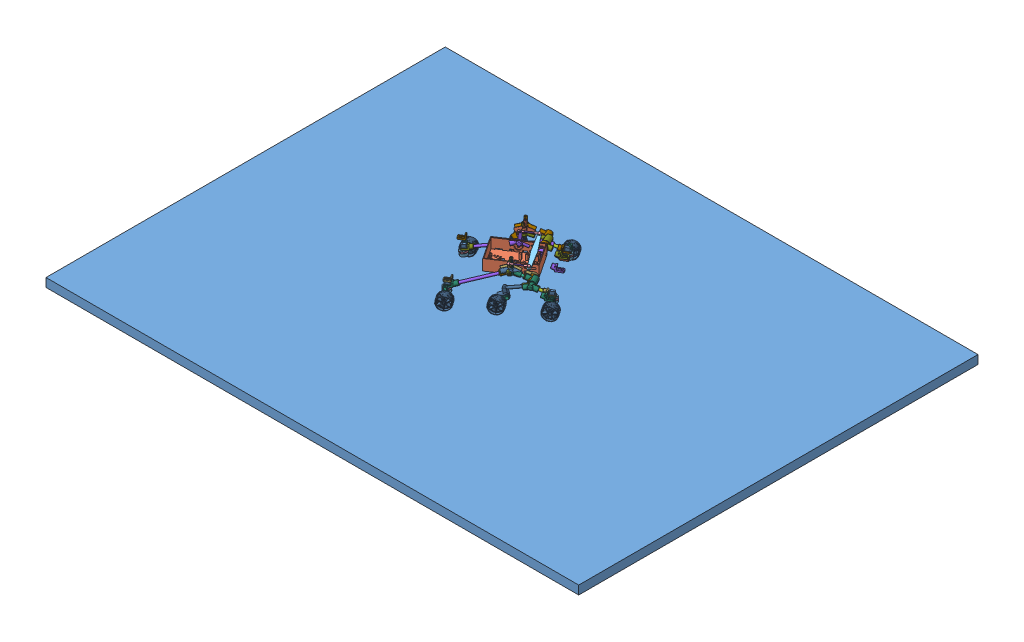
SolidWorks assembly Rover straight line sim, configuration Default. Lengths in mm.
Overall size (3078 438.66 2307).
68 component instances, 28 part files, 0 mates.
Components (placement in the parent):
- Platform for both rovers-1: Platform for both rovers [Default] at (778.954 201.0831 1288.8291) size (3078 50 2307)
- Radius Test-1: Radius Test [Default] at (196.5848 357.9283 542.8933) size (704.95 259.11 689.53)
  - Electrical Box-1: Electrical Box [Default] at (126.4667 183 218.4449) x (0.553328 0 0.832963) z (-0.832963 0 0.553328) size (183 63 235)
  - ROCKER JOINT LEFT VF-1: ROCKER JOINT LEFT VF [Default] at (89.4797 211.5 223.4649) x (0.832381 0.037395 -0.552941) z (0.553328 0 0.832963) size (91.82 74.92 47.81)
  - ROCKER JOINT RIGHT-1: ROCKER JOINT RIGHT [Default] at (4.8205 211.5 96.0216) x (0.82535 0.134896 -0.548271) z (0.553328 0 0.832963) size (91.82 74.92 46.81)
  - Differential-1: Differential [Default] at (165.5922 246 191.5125) x (0.569818 0 0.821771) z (-0.821771 0 0.569818) size (260.8 54.75 29)
  - Angled Motor-1: Angled Motor [Default] at (-200.7627 81.9301 215.203) x (-0.884031 -0.133983 0.447814) z (0.112363 -0.99086 -0.074642) size (22.4 36.6 70.6)
  - Angled Motor-2: Angled Motor [Default] at (156.5084 124.3689 -23.6932) x (-0.829613 0.036336 0.557155) z (-0.030267 -0.99934 0.020106) size (22.4 36.6 70.6)
  - Angled Motor-3: Angled Motor [Default] at (360.6875 115.5904 283.345) x (0.828628 -0.018077 -0.559508) z (-0.015058 -0.999837 0.010003) size (22.4 36.6 70.6)
  - Angled Motor-4: Angled Motor [Default] at (-30.8836 130.5292 99.3924) x (0.371576 -0.894988 -0.246834) z (-0.745493 -0.446089 0.495222) size (22.4 36.6 70.6)
  - Angled Motor-5: Angled Motor [Default] at (173.7472 118.5265 408.7321) x (-0.390629 0.883218 0.25949) z (-0.735688 -0.468963 0.488709) size (22.4 36.6 70.6)
  - Angled Motor-6: Angled Motor [Default] at (-9.5717 105.6551 527.7354) x (0.815792 0.037379 -0.577137) z (0.031149 -0.999301 -0.020692) size (22.4 36.6 70.6)
  - Bogie Pivot LEFT VF_LATEST__EVENING-1: Bogie Pivot LEFT VF_LATEST__EVENING [Default] at (150.4012 173.5055 348.669) x (0.832827 -0.018078 -0.553238) z (0.553328 0 0.832963) size (249.12 118.53 110.7)
  - Bogie Pivot RIGHT VF_LATEST__EVENING - -1: Bogie Pivot RIGHT VF_LATEST__EVENING -  [Default] at (46.1468 185.2471 188.6223) x (0.832413 -0.036337 -0.552963) z (0.553328 0 0.832963) size (249.12 118.53 161.7)
  - Bogie Pivot joint VFINAL-1: Bogie Pivot joint VFINAL [Default] at (151.1664 167.105 348.1607) x (0.832381 0.037395 -0.552941) z (0.553328 0 0.832963) size (160.51 100.01 61)
  - Bogie - Motor mount-1: Bogie - Motor mount [Default] at (151.7902 175.2726 347.2689) x (0.832304 -0.039781 -0.55289) z (0.553328 0 0.832963) size (251.14 245.94 117.56)
  - Bogie - Motor mount - RIGHT VF-1: Bogie - Motor mount - RIGHT VF [Default] at (-0.6416 186.9787 114.6395) x (0.83156 -0.058025 -0.552396) z (0.553328 0 0.832963) size (251.14 245.94 117.56)
  - Bogie Servo mount-1: Bogie Servo mount [Default] at (137.5856 173.308 329.5113) x (0.832827 -0.018078 -0.553238) z (0.553328 0 0.832963) size (471.83 118.53 111.2)
  - Servo_Connector_1-2: Servo_Connector_1 [Default] at (-30.3519 133.5126 528.9489) x (-0.356708 -0.030453 0.93372) z (-0.933697 -0.021703 -0.357407) size (40 15 40)
  - Rocker Motor mount vP-2: Rocker Motor mount vP [Default] at (-36.871 125.6068 514.3154) x (-0.356708 -0.030453 0.93372) z (-0.933697 -0.021703 -0.357407) size (42.09 25.29 45.95)
  - ROCKER SERVO JOINT VF LEFT-1: ROCKER SERVO JOINT VF LEFT [Default] at (154.6081 169.0858 343.3633) x (0.879188 0.037241 -0.475018) z (0.475457 -0.003396 0.879733) size (472.67 119.9 110.7)
  - ROCKER SERVO JOINT VF RIGHT-1: ROCKER SERVO JOINT VF RIGHT [Default] at (3.8833 168.1068 108.8694) x (0.872186 0.134339 -0.470367) z (0.476095 -0.012249 0.879308) size (474.67 119.9 110.7)
  - Differential shaft-1: Differential shaft [Default] at (183.3503 259.7267 320.1514) x (0.842799 0.000396 -0.538228) z (0.442817 -0.568942 0.692978) size (41.25 6 6)
  - Differential shaft-2: Differential shaft [Default] at (76.5142 259.6129 109.5529) x (-0.822846 -0.005173 0.568241) z (0.388203 0.725142 0.568742) size (41.25 6 6)
  - SG90 - Micro Servo 9g - Tower Pro.4-1: SG90 - Micro Servo 9g - Tower Pro.4 [Peça] at (175.9394 152.7698 2.7739) x (-0.823348 0.036332 0.566373) z (0.56673 -0.000588 0.823904) size (34.5 3.8 16.7)
  - SG90 - Micro Servo 9g - Tower Pro.1-1: SG90 - Micro Servo 9g - Tower Pro.1 [Peça] at (172.2579 172.9438 5.2196) x (-0.832413 0.036337 0.552963) z (0.553328 0 0.832963) size (32.1 29.95 12.4)
  - SG90 - Micro Servo 9g - Tower Pro.4-2: SG90 - Micro Servo 9g - Tower Pro.4 [Peça] at (-188.7747 109.7129 246.3993) x (-0.878919 -0.134149 0.457717) z (0.463546 -0.014173 0.885959) size (34.5 3.8 16.7)
  - SG90 - Micro Servo 9g - Tower Pro.1-2: SG90 - Micro Servo 9g - Tower Pro.1 [Peça] at (-186.7714 130.2248 245.0686) x (0.82535 0.134896 -0.548271) z (-0.553328 0 -0.832963) size (32.1 29.95 12.4)
  - M5 NUT ONLY-1: M5 NUT ONLY [Default] at (28.7254 259.309 143.7701) x (-0.145661 0.984591 0.096761) z (-0.820128 -0.174871 0.544802) size (28.4 25.6 9.64)
  - M5 NUT ONLY-2: M5 NUT ONLY [Default] at (98.3196 259 94.4945) size (28.4 25.6 9.64)
  - M5 NUT ONLY-3: M5 NUT ONLY [Default] at (160.4628 259.7163 333.5815) x (0.145661 -0.984591 -0.096761) z (-0.820128 -0.174871 0.544802) size (28.4 25.6 9.64)
  - M5 NUT ONLY-4: M5 NUT ONLY [Default] at (232.8648 259 288.5305) size (28.4 25.6 9.64)
  - M5 BALL-1: M5 BALL [Default] at (161.0161 259.7163 334.4145) x (-0.019674 -0.999721 0.01307) z (-0.832731 0.02362 0.553174) size (28.4 25.6 8)
  - M5 SOCKET-1: M5 SOCKET [Default] at (161.0161 259.7163 334.4145) x (0.842799 0.000396 -0.538228) z (0.006386 -0.999937 0.009265) size (28.4 10.4 12.8)
  - M5 BALL-2: M5 BALL [Default] at (28.172 259.309 142.9371) x (0.151106 0.983408 -0.100378) z (-0.819143 0.181408 0.544147) size (28.4 25.6 8)
  - M5 SOCKET-2: M5 SOCKET [Default] at (28.172 259.309 142.9371) x (0.822846 0.005173 -0.568241) z (0.19933 0.933795 0.297143) size (28.4 10.4 12.8)
  - 10mm Bearing-1: 10mm Bearing [Default] at (144.2592 211.5 305.9283) x (0.553328 0 0.832963) z (-0.832963 0 0.553328) size (8 26 26)
  - 10mm Bearing-2: 10mm Bearing [Default] at (51.8534 211.5 166.8234) x (0.553328 0 0.832963) z (-0.832963 0 0.553328) size (8 26 26)
  - SG90 - Micro Servo 9g - Tower Pro.4-5: SG90 - Micro Servo 9g - Tower Pro.4 [Peça] at (342.472 144.107 256.0722) x (0.822339 -0.018075 -0.568711) z (-0.568798 0.000338 -0.822477) size (34.5 3.8 16.7)
  - SG90 - Micro Servo 9g - Tower Pro.1-5: SG90 - Micro Servo 9g - Tower Pro.1 [Peça] at (338.4841 164.1968 258.7213) x (-0.832827 0.018078 0.553238) z (0.553328 0 0.832963) size (32.1 29.95 12.4)
  - SG90 - Micro Servo 9g - Tower Pro.4-6: SG90 - Micro Servo 9g - Tower Pro.4 [Peça] at (-29.6875 134.0965 501.7499) x (0.809304 0.037365 -0.5862) z (-0.586563 -0.001513 -0.809902) size (34.5 3.8 16.7)
  - SG90 - Micro Servo 9g - Tower Pro.1-6: SG90 - Micro Servo 9g - Tower Pro.1 [Peça] at (-26.0237 154.2751 499.316) x (0.832381 0.037395 -0.552941) z (-0.553328 0 -0.832963) size (32.1 29.95 12.4)
  - Rocker Motor mount vP-3: Rocker Motor mount vP [Default] at (183.4376 144.2883 -9.6121) x (0.379312 -0.030094 -0.924779) z (0.924774 -0.020364 0.379972) size (42.09 25.29 45.95)
  - Servo_Connector_1-5: Servo_Connector_1 [Default] at (177.2647 152.183 -24.4009) x (0.379312 -0.030094 -0.924779) z (0.924774 -0.020364 0.379972) size (40 15 40)
  - Rocker Motor mount vP-4: Rocker Motor mount vP [Default] at (334.6372 136.3502 268.7221) x (-0.377336 0.014947 0.925956) z (-0.925954 0.010169 -0.377499) size (42.09 25.29 45.95)
  - Servo_Connector_1-6: Servo_Connector_1 [Default] at (341.2081 144.3979 283.2547) x (-0.377336 0.014947 0.925956) z (-0.925954 0.010169 -0.377499) size (40 15 40)
  - Rocker Motor mount vP-5: Rocker Motor mount vP [Default] at (-178.7715 103.681 234.3526) x (0.48227 0.120058 -0.867757) z (0.868786 0.061507 0.491352) size (42.09 25.29 45.95)
  - Servo_Connector_1-7: Servo_Connector_1 [Default] at (-184.2996 112.2335 219.675) x (0.48227 0.120058 -0.867757) z (0.868786 0.061507 0.491352) size (40 15 40)
  - Rocker P to Bogie P-1: Rocker P to Bogie P [Default] at (214.3964 195.0374 285.1484) x (-0.590232 -0.549348 -0.591475) z (-0.798011 0.28664 0.53011) size (14.05 15.92 38.63)
  - Rocker P to Bogie P-2: Rocker P to Bogie P [Default] at (99.2589 201.9508 109.521) x (0.544848 0.562783 0.621623) z (-0.817528 0.191621 0.543075) size (14.05 15.92 38.63)
  - 10mm Bearing-3: 10mm Bearing [Default] at (250.1693 186.8587 289.5974) x (0.553328 0 0.832963) z (-0.832025 0.047462 0.552705) size (8 26 26)
  - 10mm Bearing-4: 10mm Bearing [Default] at (109.5823 196.4833 74.4508) x (-0.553328 0 -0.832963) z (-0.71773 0.507489 0.47678) size (8 26 26)
  - Bogie Pivot joint VFINAL-3: Bogie Pivot joint VFINAL [Default] at (35.8382 267.3766 130.6413) x (0.722474 -0.497692 -0.479931) z (-0.553328 0 -0.832963) size (160.51 100.01 61)
  - Bogie P to Servo M-1: Bogie P to Servo M [Default] at (115.0087 189.0592 43.2495) x (0.778249 -0.356451 -0.516982) z (-0.012465 -0.831885 0.554808) size (40.99 16.26 14.42)
  - Bogie P to Servo M-2: Bogie P to Servo M [Default] at (281.4662 179.0541 297.6105) x (0.783542 -0.339326 -0.520499) z (-0.608397 -0.589078 -0.531827) size (40.99 16.26 14.42)
  - R to R arm-1: R to R arm [Default] at (131.6688 205.6612 344.9596) x (-0.672895 -0.267168 0.689806) z (-0.337979 0.940518 0.034577) size (192.48 14 16.99)
  - R to R arm-2: R to R arm [Default] at (11.5968 202.5529 162.8978) x (-0.871207 -0.357986 0.335923) z (0.325926 0.089924 0.941109) size (192.48 14 16.99)
  - M5 SOCKET-3: M5 SOCKET [Default] at (232.8648 259.75 288.5305) x (-0.842799 -0.000396 0.538228) z (-0.483953 -0.437064 -0.758133) size (28.4 10.4 12.8)
  - M5 BALL-3: M5 BALL [Default] at (232.8648 259.75 288.5305) x (0.695254 0 0.718764) z (-0.718764 0 0.695254) size (28.4 25.6 8)
  - M5 SOCKET-4: M5 SOCKET [Default] at (98.3196 259.75 94.4945) x (-0.822846 -0.005173 0.568241) z (-0.568254 0.001459 -0.822852) size (28.4 10.4 12.8)
  - M5 BALL-4: M5 BALL [Default] at (98.3196 259.75 94.4945) x (0.695254 0 0.718764) z (-0.718764 0 0.695254) size (28.4 25.6 8)
  - Bogie Servo mount RIGHT -5: Bogie Servo mount RIGHT  [Default] at (-16.3002 185.8254 94.2236) x (0.832413 -0.036337 -0.552963) z (0.553328 0 0.832963) size (471.83 118.53 104.3)
  - Wheel V2-1: Wheel V2 [Default] at (10.3911 104.7905 554.4045) x (0.816386 -0.000304 -0.577506) z (0.577506 0.001097 0.816385) size (75 75 44.03)
  - Wheel V2-2: Wheel V2 [Default] at (192.9193 117.6257 435.974) x (0.832963 0 -0.553328) z (0.553328 0 0.832963) size (75 75 44.03)
  - Wheel V2-3: Wheel V2 [Default] at (380.3613 115.3804 310.2412) x (0.671801 0.585667 -0.453517) z (0.559598 -0.000136 0.828764) size (75 75 44.03)
  - Wheel V2-4: Wheel V2 [Default] at (-216.0963 81.2047 185.625) x (-0.744003 -0.556999 0.369069) z (-0.453721 0.015668 -0.891006) size (75 75 44.03)
  - Wheel V2-5: Wheel V2 [Default] at (-49.5233 129.2849 71.7968) x (-0.697107 -0.547355 0.463081) z (-0.553328 0 -0.832963) size (75 75 44.03)
  - Wheel V2-6: Wheel V2 [Default] at (137.7336 123.1297 -51.1973) x (-0.693143 -0.550434 0.465376) z (-0.557518 0.000183 -0.830165) size (75 75 44.03)
